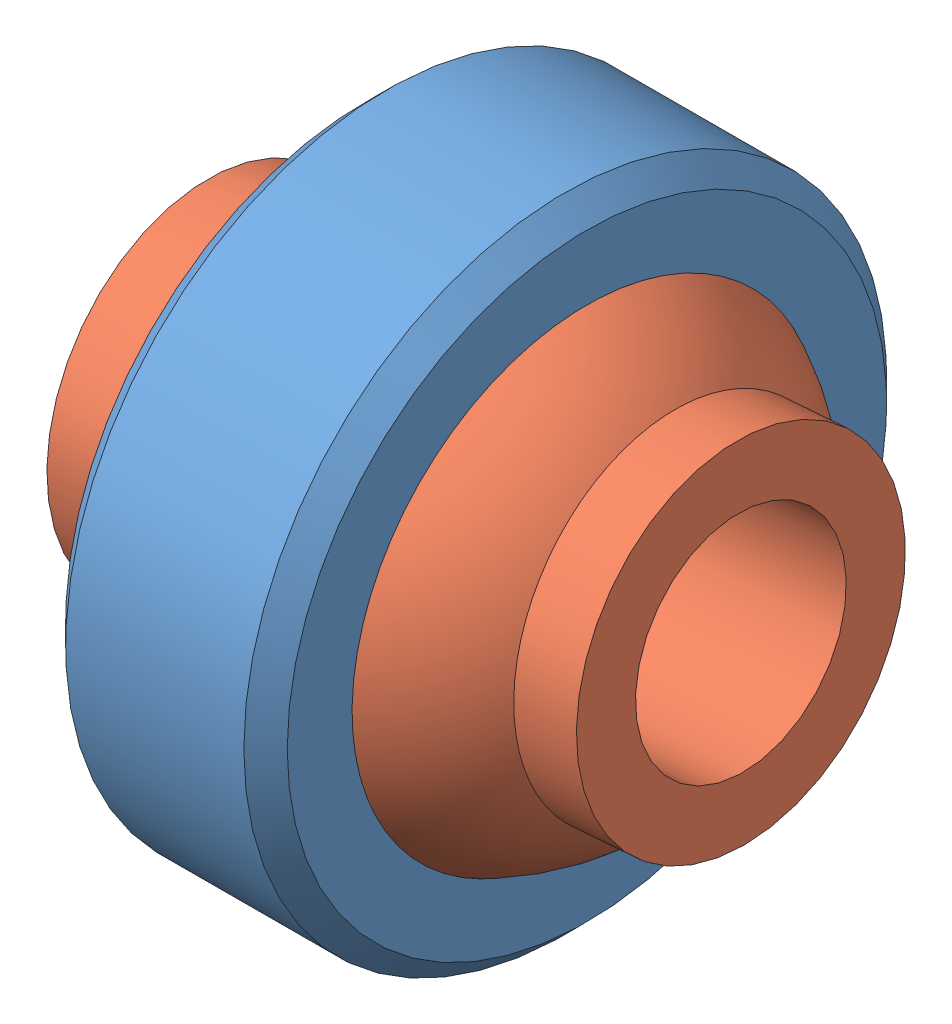
SolidWorks assembly swivel_bearing, configuration Default. Lengths in mm.
Overall size (15.95 22.06 21.84).
2 component instances, 2 part files, 2 mates.
Components (placement in the parent):
- ball2-1: ball2 [Default] at origin size (6.48 18.8 18.8)
- ball-1: ball [Default] x (0.998561 0.044861 -0.029373) z (-0.007044 0.652769 0.757524) size (15.06 15.18 15.18)
Mates (geometry in assembly coordinates):
- Coincident3: coordinate: point of ball2-1; point of assembly
- Concentric1: concentric: sphere of ball2-1; sphere of ball-1
